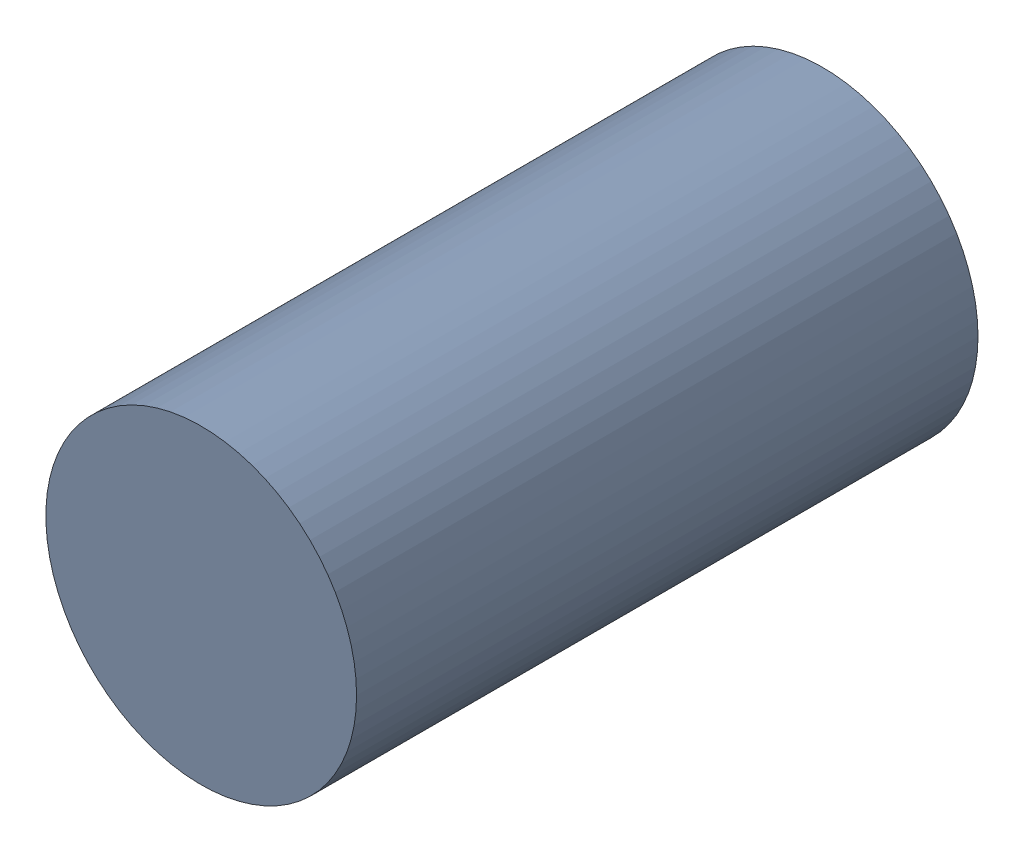
SolidWorks assembly MH5_1.step, configuration Default. Lengths in mm.
Overall size (1 1 2).
2 component instances, 1 part files, 0 mates.
Components (placement in the parent):
- 9228463120_1.step-11: 9228463120_1.step [Default] at (487.68 316.992 -1.5) size (1 1 2)
  - Cylinder_1.step-98: Cylinder_1.step [Default] at origin size (1 1 2)
